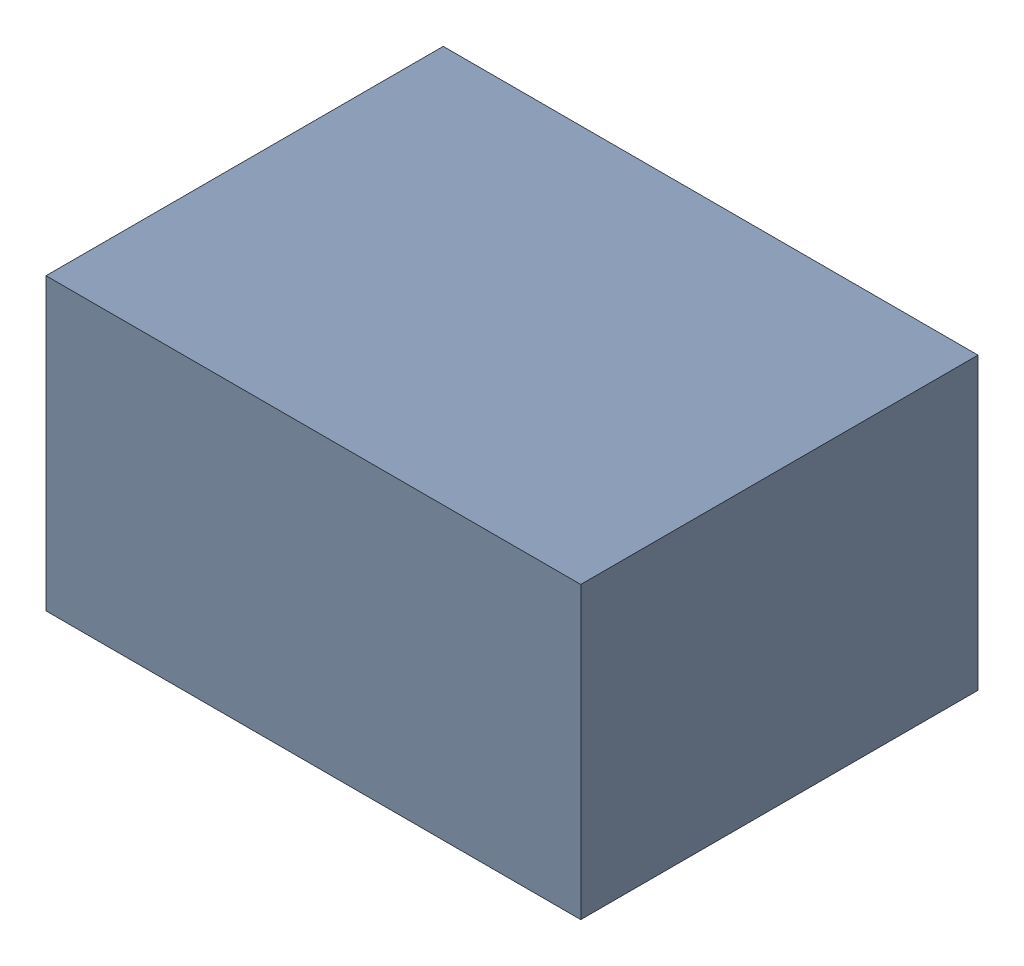
SolidWorks assembly C1, configuration Default. Lengths in mm.
Overall size (1.75 0.95 1.3).
2 component instances, 1 part files, 0 mates.
Components (placement in the parent):
- 4438510656-1: 4438510656 [Default] at (15.24 23.684 0) size (1.75 0.95 1.3)
  - Extruded_5-1: Extruded_5 [Default] at origin size (1.75 0.95 1.3)
